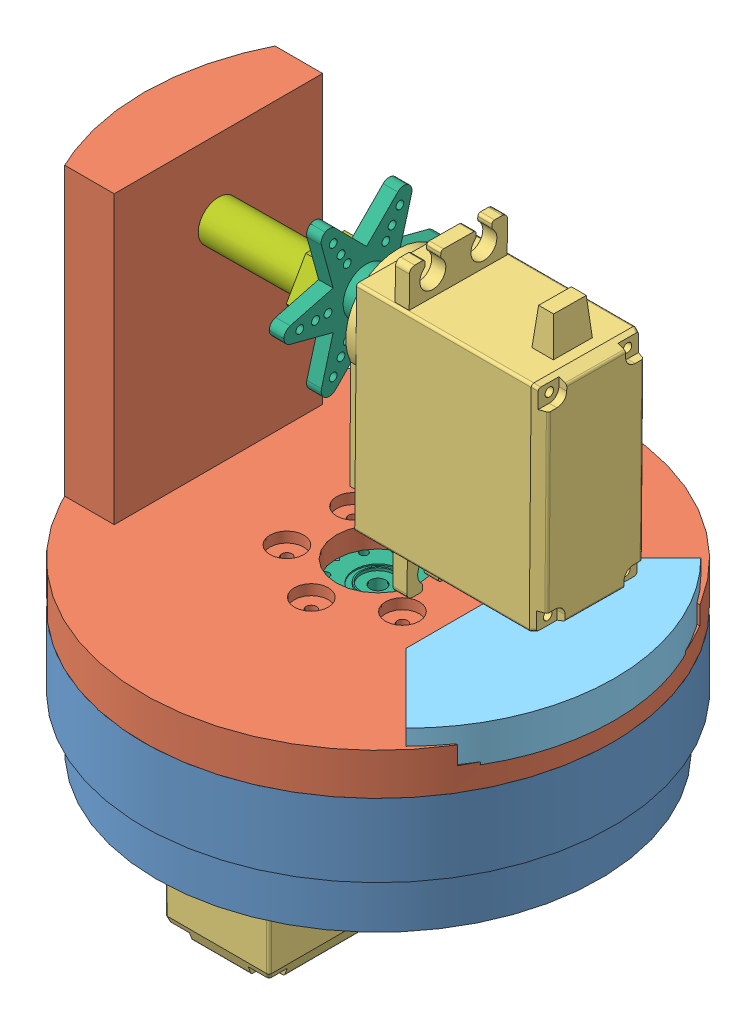
SolidWorks assembly PanAndTilt, configuration Default. Lengths in mm.
Overall size (90.55 114.12 90).
13 component instances, 8 part files, 20 mates.
Components (placement in the parent):
- basePanTilt-1: basePanTilt [Default] at (34.1107 41.4873 83.0065) size (90 24 90)
- Part2^PanAndTilt-1: Part2^PanAndTilt [Default] at (34.1107 55.4873 83.0065) x (1 0 0) z (0 1 0) size (90 90 63) (virtual)
- MG996R-ServoMotor-3: MG996R-ServoMotor [Default] at (18.8732 8.4088 49.9532) size (20 44.02 55)
  - MG996R-ServoMotor-1: MG996R-ServoMotor [Default] at (5.2376 21.8785 43.4533) size (20 40 55)
  - MG996R-Gear-1: MG996R-Gear [Default] at (5.3909 -12.8534 33.0533) size (6 6.02 6)
- MG996R-ServoMotor-7: MG996R-ServoMotor [Default] at (78.5608 138.6065 66.2528) x (0 0.008727 0.999962) z (0 -0.999962 0.008727) size (20 44.02 55)
  - MG996R-ServoMotor-1: MG996R-ServoMotor [Default] at (5.2376 21.8785 43.4533) size (20 40 55)
  - MG996R-Gear-1: MG996R-Gear [Default] at (5.3909 -12.8534 33.0533) size (6 6.02 6)
- Part3^PanAndTilt-1: Part3^PanAndTilt [Default] at (5.5467 63.4873 166.1735) x (-1 0 0) z (0 1 0) size (25 56.57 7) (virtual)
- Servo Horn8-1: Servo Horn8 [Default] at (34.1107 59.4873 83.0065) x (0.5 0 0.866025) z (0.866025 0 -0.5) size (27.89 6.25 31.75)
- Servo Horn8-2: Servo Horn8 [Default] at (27.8823 105.6874 81.7783) x (0 0.5 0.866025) z (0 0.866025 -0.5) size (27.89 6.25 31.75)
- Part5^PanAndTilt-1: Part5^PanAndTilt [Default] at (28.5027 35.3149 38.6315) x (0.008727 0 0.999962) z (-0.999962 0 0.008727) size (15.01 13 35.5) (virtual)
- instrument ball bearing_68_am-2: instrument ball bearing_68_am [AFBMA 12.1.4.1 - 0080-22 - 8,DE,NC,8_68] at (-3.3245 104.0246 82.6647) x (0.999962 0 -0.008727) z (0.008727 0 0.999962) size (7 22 22)
Mates (geometry in assembly coordinates):
- InPlace1: in place: plane of basePanTilt-1 through (34.1107 49.4873 83.0065) normal (0 1 0); plane of ? through (0 49.4873 0) normal (0 1 0); moOrthogonalPlaneRef_w of basePanTilt-1 through (34.1107 49.4873 83.0065) normal (0 1 0); plane of ? through (0 49.4873 0) normal (0 0 -1); plane of basePanTilt-1 through (34.1107 49.4873 83.0065) normal (0 1 0); line of ? through (-55 0 49.4873) axis (0 1 0); plane of basePanTilt-1 through (34.1107 55.4873 83.0065) normal (0 1 0); unknown of Part2^PanAndTilt-1
- Coincident1: coincident aligned: plane of basePanTilt-1; plane of Part2^PanAndTilt-1
- Coincident2: coincident aligned: moOrthogonalPlaneRef_w of basePanTilt-1 through (34.1107 55.4873 83.0065) normal (0 0 -1); plane of Part2^PanAndTilt-1 through (34.1107 55.4873 83.0065) normal (0 0 -1)
- Coincident3: coincident anti-aligned: moOrthogonalPlaneRef_w of basePanTilt-1 through (34.1107 55.4873 83.0065) normal (-1 0 0); plane of Part2^PanAndTilt-1
- Concentric1: concentric anti-aligned: cylinder of basePanTilt-1 through (34.1107 55.4873 83.0065) axis (0 -1 0) radius 11.5; cylinder of MG996R-ServoMotor-3/MG996R-Gear-1 through (34.1107 48.2873 83.0065) axis (0 1 0) radius 1.5
- Concentric2: concentric aligned: cylinder of MG996R-ServoMotor-3/MG996R-Gear-1 through (34.1107 40.4873 83.0065) axis (0 1 0) radius 1.5; cylinder of ? through (34.1107 49.4873 83.0065) axis (0 1 0) radius 3
- Coincident5: coincident anti-aligned: plane of MG996R-ServoMotor-3/MG996R-Gear-1 through (37.1107 48.4873 83.0065) normal (0 1 0); plane of ? through (34.1107 48.4873 83.0065) normal (0 -1 0)
- Concentric3: concentric aligned: circle of MG996R-ServoMotor-3/MG996R-Gear-1; cylinder of ? through (34.1107 52.9373 83.0065) axis (0 1 0) radius 3
- Coincident6: coincident anti-aligned: plane of MG996R-ServoMotor-3/MG996R-Gear-1 through (37.1107 56.2873 83.0065) normal (0 1 0); plane of ? through (44.1319 56.2873 133.626) normal (0 -1 0)
- Coincident7: coincident anti-aligned: plane of Part2^PanAndTilt-1 through (34.1107 54.9873 83.0065) normal (0 1 0); plane of ? through (31.9145 54.9873 81.5989) normal (0 -1 0)
- Parallel5: parallel aligned: plane of ? through (13.9145 54.9873 102.0989) normal (-1 0 0); plane of ? through (24.1107 21.9873 93.4065) normal (-1 0 0)
- Coincident8: coincident anti-aligned: plane of basePanTilt-1 through (34.1107 41.4873 83.0065) normal (0 -1 0); plane of MG996R-ServoMotor-3/MG996R-ServoMotor-1 through (24.7107 41.4873 65.9065) normal (0 1 0)
- Parallel7: parallel anti-aligned: plane of Part2^PanAndTilt-1 through (69.1391 59.9873 83.0065) normal (1 0 0); plane of Part3^PanAndTilt-1 through (54.6574 66.4873 166.1735) normal (-1 0 0)
- Coincident9: coincident anti-aligned: plane of Part2^PanAndTilt-1 through (34.1107 63.4873 83.0065) normal (0 1 0); plane of Part3^PanAndTilt-1 through (5.5467 63.4873 166.1735) normal (0 -1 0)
- Concentric4: concentric anti-aligned: cylinder of Part2^PanAndTilt-1 through (45.1959 79.4873 89.4065) axis (0 -1 0) radius 1; cylinder of Servo Horn8-1 through (45.1959 56.6873 89.4065) axis (0 1 0) radius 0.75
- Coincident10: coincident anti-aligned: plane of Part2^PanAndTilt-1 through (34.1107 59.4873 83.0065) normal (0 -1 0); plane of Servo Horn8-1 through (21.8154 59.4873 75.8465) normal (0 1 0)
- Concentric5: concentric anti-aligned: cylinder of Part2^PanAndTilt-1 through (45.1959 79.4873 76.6065) axis (0 -1 0) radius 1; cylinder of Servo Horn8-1 through (45.1959 56.6873 76.6065) axis (0 1 0) radius 0.75
- Concentric6: concentric aligned: cylinder of MG996R-ServoMotor-7/MG996R-Gear-1 through (38.6823 105.6874 81.7783) axis (-1 0 0) radius 1.5; cylinder of Servo Horn8-2 through (30.6823 105.6874 81.7783) axis (-1 0 0) radius 1.5
- Coincident11: coincident anti-aligned: plane of MG996R-ServoMotor-7/MG996R-Gear-1 through (30.6823 105.7136 84.7781) normal (-1 0 0); plane of Servo Horn8-2 through (30.6823 93.3921 74.6183) normal (1 0 0)
- Concentric7: concentric aligned: cylinder of Part5^PanAndTilt-1 through (-6.6142 104.0246 82.6934) axis (0.999962 0 -0.008727) radius 3.9; cylinder of instrument ball bearing_68_am-2 through (-23.9613 104.0246 82.8448) axis (0.999962 0 -0.008727) radius 4
